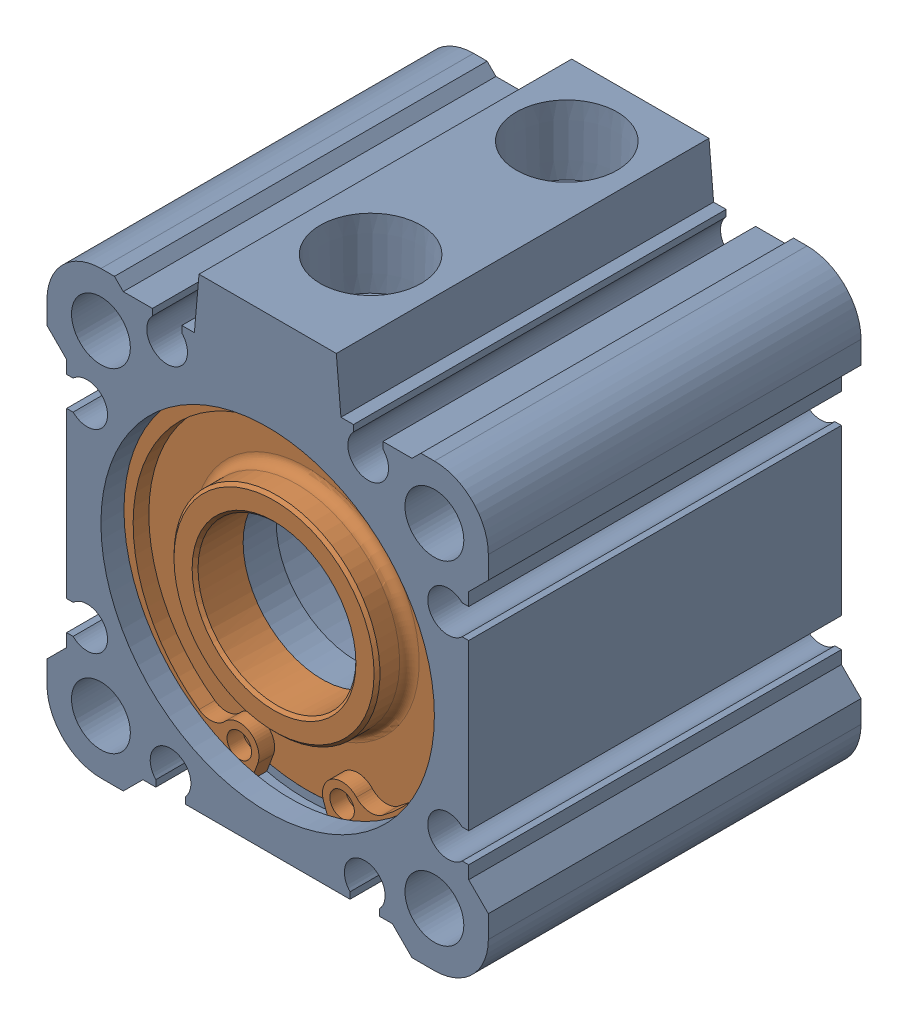
SolidWorks assembly NCQ2A32-15DZ_NCQ2A32-15DZ, configuration Default. Lengths in mm.
Overall size (45 49.5 38).
2 component instances, 2 part files, 0 mates.
Components (placement in the parent):
- NCQ2A32-15DZ_CQ2Tube_32-1: NCQ2A32-15DZ_CQ2Tube_32 [Default] at origin size (45 49.5 38)
- NCQ2A32-15DZ_CQ2 SnapRing_32-1: NCQ2A32-15DZ_CQ2 SnapRing_32 [Default] at (0 0 15.05) size (35.7 35.24 4.9)
